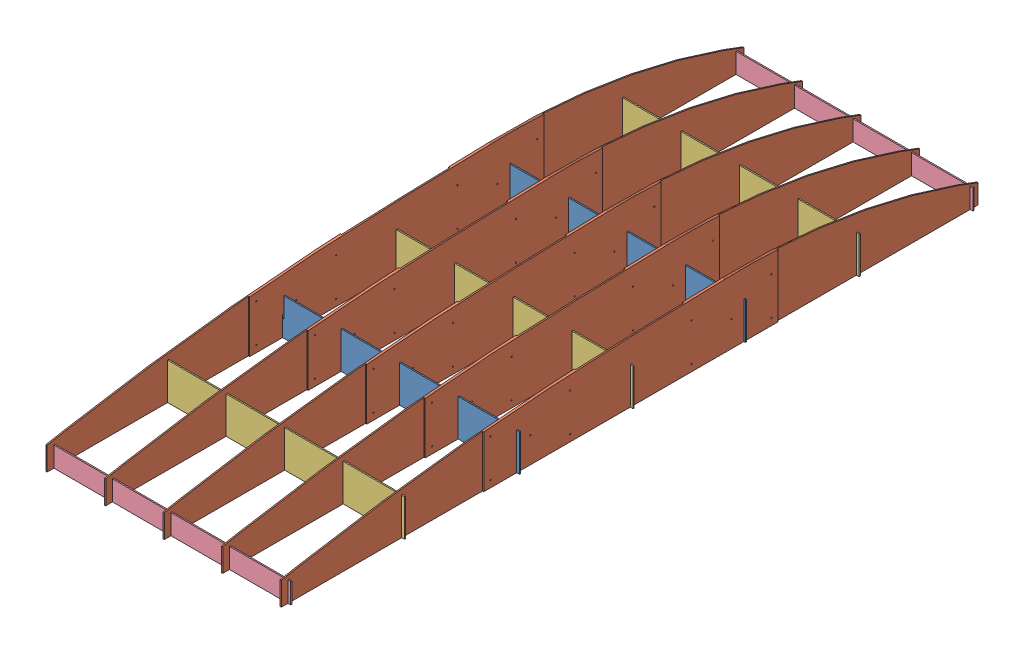
SolidWorks assembly eggcrate, configuration Default. Lengths in mm.
Overall size (1838.2 508 5291.29).
12 component instances, 4 part files, 34 mates.
Components (placement in the parent):
- 11indouble-1: 11indouble [Default] at (-7919.0519 -26087.862 862.944) x (0 1 0) z (0 0 -1) size (279.4 1828.8 9.4)
- thetop(lid-1: thetop(lid [Default] at (-9.398 0 -4.699) x (1 0 0.000002) z (-0.000002 0 1) size (18.8 484.05 5291.29)
- 11indouble-2: 11indouble [Default] at (7900.256 -26087.862 -872.342) x (0 1 0) z (0 0 1) size (279.4 1828.8 9.4)
- 11inrib-1: 11inrib [Default] at (7900.2573 -25466.6209 -1735.942) x (0 1 0) z (0 0 1) size (279.4 1828.8 9.4)
- 11inrib-2: 11inrib [Default] at (7909.6526 -25466.6209 -9.398) x (0 1 0) z (0 0 1) size (279.4 1828.8 9.4)
- 11inrib-3: 11inrib [Default] at (7900.2518 -25466.6209 1717.146) x (0 1 0) z (0 0 1) size (279.4 1828.8 9.4)
- 3inrib-1: 3inrib [Default] at (-7928.4527 -25084.5465 2590.144) x (0 1 0) z (0 0 -1) size (152.4 1828.8 9.4)
- 3inrib-2: 3inrib [Default] at (7900.2587 -25084.5465 -2599.5421) x (0 1 0) z (0 0 1) size (152.4 1828.8 9.4)
- thetop(lid-2: thetop(lid [Default] at (-453.898 0 -4.699) x (1 0 0.000002) z (-0.000002 0 1) size (18.8 484.05 5291.29)
- thetop(lid-3: thetop(lid [Default] at (-898.398 0 -4.699) x (1 0 0.000002) z (-0.000002 0 1) size (18.8 484.05 5291.29)
- thetop(lid-4: thetop(lid [Default] at (435.102 0 -4.699) x (1 0 0.000002) z (-0.000002 0 1) size (18.8 484.05 5291.29)
- thetop(lid-5: thetop(lid [Default] at (879.602 0 -4.699) x (1 0 0.000002) z (-0.000002 0 1) size (18.8 484.05 5291.29)
Mates (geometry in assembly coordinates):
- Perpendicular1: perpendicular: line of 11indouble-1 through (909.6996 0 862.944) axis (-1 0 0)
- Coincident7: coincident anti-aligned: plane of 11indouble-1 through (-7919.0519 0 853.546) normal (0 -1 0)
- Coincident11: coincident: point of thetop(lid-1
- Coincident12: coincident aligned: line of 11indouble-1 through (-0.0014 279.4 853.546) axis (0 -1 0); line of thetop(lid-1 through (-0.0014 152.4 853.546) axis (0 -1 0)
- Parallel2: parallel aligned: plane of 11indouble-1 through (-7919.0519 -26087.862 853.546) normal (0 0 -1); plane of 11indouble-2 through (7900.256 -26087.862 -872.342) normal (0 0 -1)
- Coincident14: coincident anti-aligned: plane of 11indouble-2 through (7900.256 0 -862.944) normal (0 -1 0)
- Coincident16: coincident anti-aligned: line of thetop(lid-1 through (0.0014 152.4 -872.342) axis (0 -1 0); line of 11indouble-2 through (0.0014 127 -872.342) axis (0 1 0)
- Coincident17: coincident: line of 11inrib-1 through (-928.4942 0 -1726.544) axis (1 0 0)
- Parallel3: parallel anti-aligned: plane of 11indouble-2 through (7900.256 -26087.862 -862.944) normal (0 0 1); plane of 11inrib-1 through (7900.2573 -25466.6209 -1735.942) normal (0 0 -1)
- Coincident19: coincident aligned: line of thetop(lid-1 through (-9.3952 0 -1726.544) axis (0 1 0); line of 11inrib-1 through (-9.3952 127 -1726.544) axis (0 1 0)
- Coincident20: coincident aligned: line of thetop(lid-1 through (152.4 0 0) axis (0 0 1); line of 11inrib-2 through (152.4 0 127) axis (0 0 1)
- Coincident21: coincident: line of 11inrib-2 through (1828.8 -919.099 0) axis (0 1 0)
- Parallel4: parallel aligned: plane of 11indouble-2 through (7900.256 -26087.862 -862.944) normal (0 0 1); plane of 11inrib-2 through (7909.6526 -25466.6209 0) normal (0 0 1)
- Coincident23: coincident anti-aligned: line of thetop(lid-1 through (-9.4008 152.4 1726.544) axis (0 -1 0); line of 11inrib-3 through (-9.4008 127 1726.544) axis (0 1 0)
- Coincident24: coincident: line of 11inrib-3 through (-928.4998 0 1726.544) axis (1 0 0)
- Parallel5: parallel aligned: plane of 11indouble-1 through (-7919.0519 -26087.862 862.944) normal (0 0 1); plane of 11inrib-3 through (7900.2518 -25466.6209 1726.544) normal (0 0 1)
- Coincident33: coincident anti-aligned: plane of 3inrib-1 through (-7928.4527 0 2580.746) normal (0 -1 0)
- Parallel9: parallel aligned: plane of 11inrib-3 through (7900.2518 -25466.6209 1726.544) normal (0 0 1); plane of 3inrib-1 through (-7928.4527 -25084.5465 2590.144) normal (0 0 1)
- Coincident35: coincident aligned: line of thetop(lid-1 through (-9.4021 76.2 2590.144) axis (0 -1 0); line of 3inrib-1 through (-9.4021 152.4 2590.144) axis (0 -1 0)
- Coincident37: coincident anti-aligned: plane of 3inrib-2 through (7900.2587 0 -2590.1441) normal (0 -1 0)
- Coincident38: coincident aligned: line of thetop(lid-1 through (-18.7918 76.2 -2599.5421) axis (0 -1 0); line of 3inrib-2 through (-18.7918 152.4 -2599.5421) axis (0 -1 0)
- Parallel10: parallel aligned: plane of 11inrib-1 through (7900.2573 -25466.6209 -1735.942) normal (0 0 -1); plane of 3inrib-2 through (7900.2587 -25084.5465 -2599.5421) normal (0 0 -1)
- Coincident40: coincident anti-aligned: line of 11indouble-2 through (-463.2946 279.4 -862.944) axis (0 -1 0); line of thetop(lid-2 through (-463.2946 0 -862.944) axis (0 1 0)
- Coincident41: coincident anti-aligned: plane of thetop(lid-2 through (-444.5 0 -9.398) normal (0 -1 0)
- Coincident43: coincident anti-aligned: line of 11inrib-3 through (-463.2988 279.4 1717.146) axis (0 -1 0); line of thetop(lid-2 through (-463.2988 0 1717.146) axis (0 1 0)
- Coincident45: coincident aligned: line of 11indouble-2 through (-907.7946 279.4 -872.342) axis (0 -1 0); line of thetop(lid-3 through (-907.7946 152.4 -872.342) axis (0 -1 0)
- Parallel11: parallel aligned: plane of thetop(lid-2 through (-463.296 0 -4.699) normal (-1 0 -0.000002); plane of thetop(lid-3 through (-907.796 0 -4.699) normal (-1 0 -0.000002)
- Coincident47: coincident aligned: plane of 11indouble-2 through (7900.256 0 -862.944) normal (0 -1 0); plane of thetop(lid-3 through (-888.9986 0 -872.342) normal (0 -1 0)
- Coincident48: coincident aligned: line of thetop(lid-4 through (444.5014 0 -862.944) axis (0 1 0); line of 11indouble-2 through (444.5014 127 -862.944) axis (0 1 0)
- Parallel12: parallel aligned: plane of thetop(lid-1 through (0.0014 -4451.5504 -857.1289) normal (1 0 0.000002); plane of thetop(lid-4 through (444.5014 -4451.5504 -857.1289) normal (1 0 0.000002)
- Coincident51: coincident: line of 11indouble-2 through (-928.4956 0 -862.944) axis (1 0 0); plane of thetop(lid-4 through (444.5 0 -9.398) normal (0 -1 0)
- Coincident54: coincident aligned: plane of 11indouble-2 through (7900.256 0 -862.944) normal (0 -1 0); plane of thetop(lid-5 through (888.9986 0 853.546) normal (0 -1 0)
- Parallel15: parallel aligned: plane of thetop(lid-4 through (444.5014 -4451.5504 -857.1289) normal (1 0 0.000002); plane of thetop(lid-5 through (889.0014 -4451.5504 -857.1289) normal (1 0 0.000002)
- Coincident57: coincident anti-aligned: line of 3inrib-2 through (879.6062 76.2 -2599.5421) axis (0 1 0); line of thetop(lid-5 through (879.6062 76.2 -2599.5421) axis (0 -1 0)
